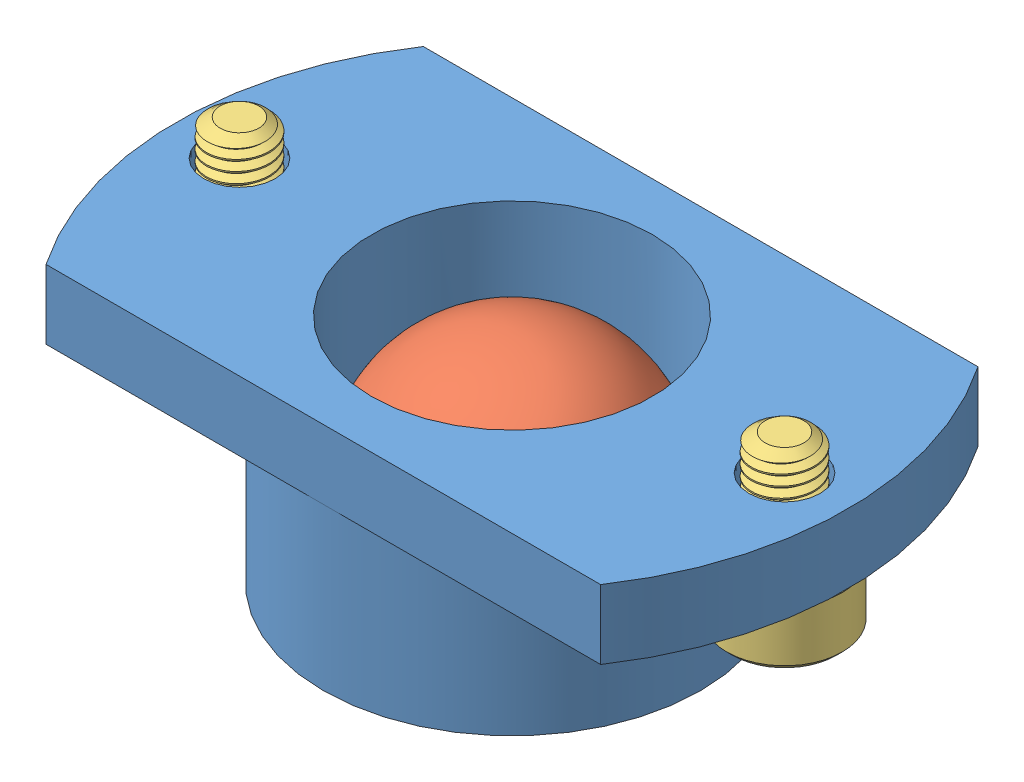
SolidWorks assembly Omni_Bearing, configuration Default. Lengths in mm.
Overall size (32 21.7 19.65).
4 component instances, 3 part files, 5 mates.
Components (placement in the parent):
- Omni_Bearing_Holder-1: Omni_Bearing_Holder [Default] at (-19.5215 0.8894 9.3573) size (32 11 18)
- Ball Bearing 1cm-1: Ball Bearing 1cm [Default] at (-19.5215 0.8894 9.3573) x (0.884877 0.437275 0.160575) z (-0.43654 0.658126 0.613435) size (12.7 12.7 12.7)
- Screw SC M3 x 5-1: Screw SC M3 x 5 [92290A110] at (-6.5215 9.5894 9.3573) x (1 0 0) z (0 1 0) size (5.5 5.5 8.58)
- Screw SC M3 x 5-2: Screw SC M3 x 5 [92290A110] at (-32.5215 9.5894 9.3573) x (1 0 0) z (0 1 0) size (5.5 5.5 8.58)
Mates (geometry in assembly coordinates):
- Concentric1: concentric: sphere of Omni_Bearing_Holder-1; sphere of Ball Bearing 1cm-1
- Concentric2: concentric anti-aligned: cylinder of Omni_Bearing_Holder-1 through (-32.5215 4.5894 9.3573) axis (0 -1 0) radius 1.7; circle of Screw SC M3 x 5-2
- Coincident1: coincident: plane of Omni_Bearing_Holder-1 through (-19.5215 4.5894 9.3573) normal (0 -1 0); plane of Screw SC M3 x 5-1 through (0.313 4.5894 16.3299) normal (0 1 0)
- Coincident2: coincident anti-aligned: plane of Omni_Bearing_Holder-1 through (-19.5215 4.5894 9.3573) normal (0 -1 0); plane of Screw SC M3 x 5-2 through (-32.5215 4.5894 9.3573) normal (0 1 0)
- Concentric3: concentric anti-aligned: cylinder of Omni_Bearing_Holder-1 through (-6.5215 4.5894 9.3573) axis (0 -1 0) radius 1.7; circle of Screw SC M3 x 5-1
